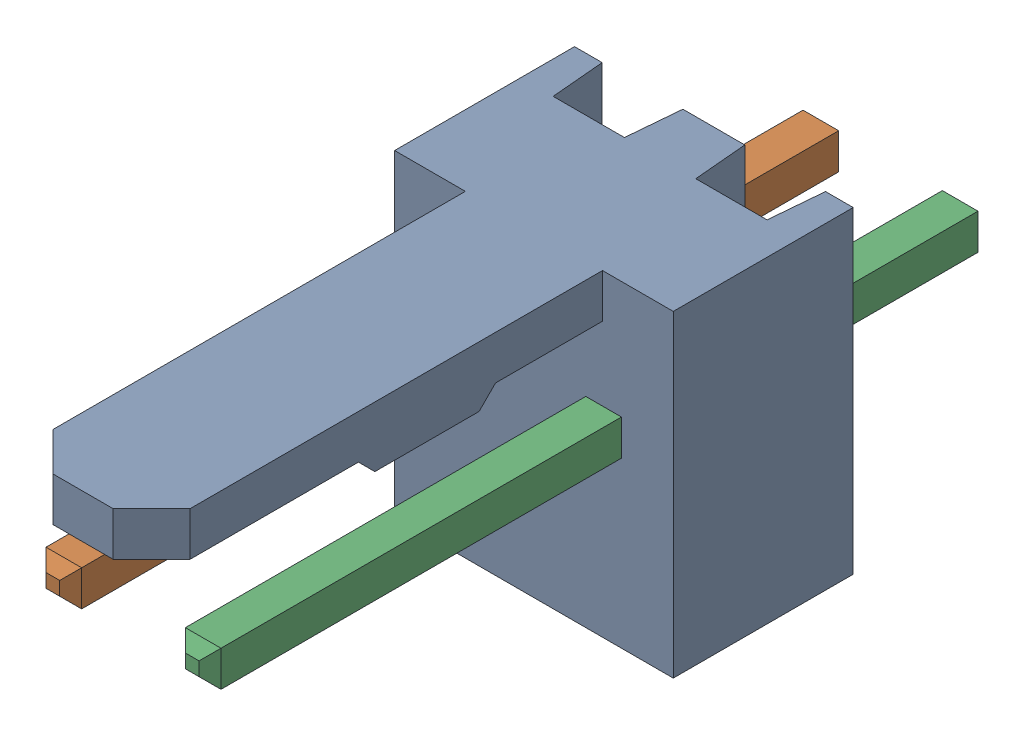
SolidWorks assembly Molex PCB 2 pin v2_3, configuration Default. Lengths in mm.
Overall size (5.08 5.79 14.92).
3 component instances, 2 part files, 0 mates.
Components (placement in the parent):
- BASE9710016_1-1: BASE9710016_1 [Default] at (2.54 2.895 -8.22) size (5.08 5.79 11.5)
- PINO9710016_1-1: PINO9710016_1 [Default] at (1.27 3.325 -0.72) size (0.65 0.65 14.2)
- PINO9710016_1-2: PINO9710016_1 [Default] at (3.81 3.325 -0.72) size (0.65 0.65 14.2)
